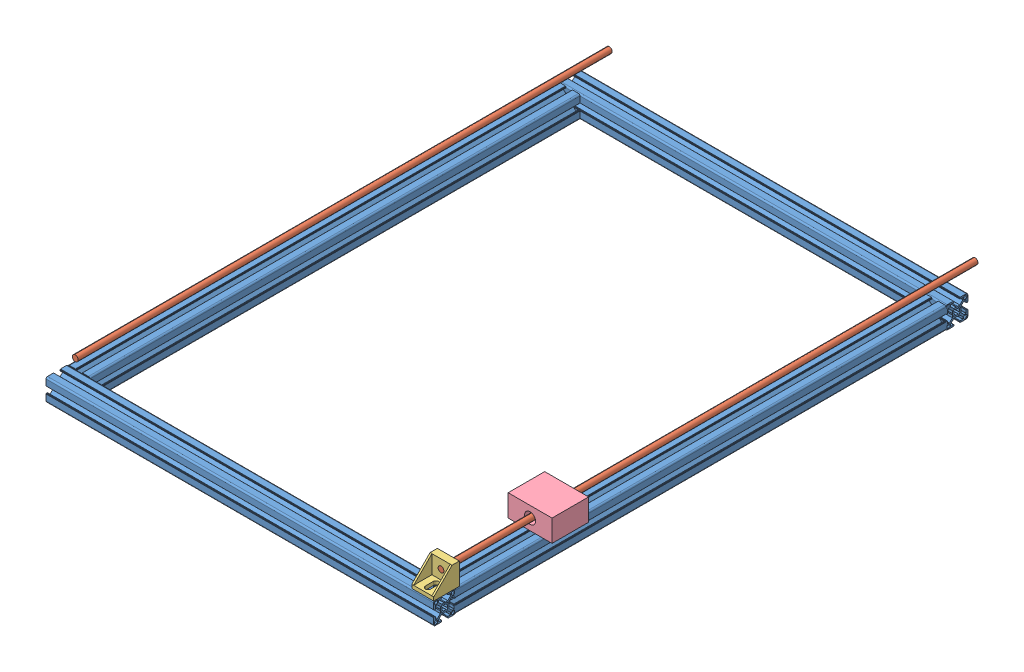
SolidWorks assembly Assem1, configuration Default. Lengths in mm.
Overall size (545 62.5 755).
4 component instances, 4 part files, 6 mates.
Components (placement in the parent):
- Alu Profil-1: Alu Profil [Default<As Machined>] at (265.2054 410.9312 543.815) x (0 0 -1) z (1 0 0) size (730 30 530)
- X Axis Rods-1: X Axis Rods [Default<As Machined>] at (265.2054 413.0471 518.815) x (0 0 -1) z (1 0 0) size (730 8 508)
- Round Profil holder-1: Round Profil holder [Default] at (515.2054 443.4312 873.815) size (30 30 35)
- X Axis Roller-1: X Axis Roller [Default] at (265.2054 443.4312 737.1166) size (60 30 50)
Mates (geometry in assembly coordinates):
- Coincident4: coincident: plane of Alu Profil-1 through (530.2054 425.9312 889.065) normal (0 1 0); plane of Round Profil holder-1 through (515.2054 425.9312 873.815) normal (0 -1 0)
- Coincident5: coincident: plane of Alu Profil-1 through (530.2054 423.9312 908.815) normal (0 0 1); plane of Round Profil holder-1 through (500.2054 425.9312 908.815) normal (0 0 1)
- Coincident6: coincident: plane of Alu Profil-1 through (530.2054 398.3312 201.865) normal (1 0 0); plane of Round Profil holder-1 through (530.2054 455.9312 883.815) normal (1 0 0)
- Concentric1: concentric: cylinder of X Axis Rods-1 through (515.2054 443.4312 166.8343) axis (0 0 1) radius 4; cylinder of Round Profil holder-1 through (515.2054 443.4312 883.815) axis (0 0 -1) radius 4
- Concentric2: concentric: cylinder of X Axis Rods-1 through (515.2054 443.4312 153.815) axis (0 0 1) radius 4; cylinder of X Axis Roller-1 through (515.2054 443.4312 762.1166) axis (0 0 -1) radius 7.5
- Coincident7: coincident: plane of X Axis Rods-1 through (515.2054 443.4312 883.815) normal (0 0 1); plane of Round Profil holder-1 through (515.2054 443.4312 883.815) normal (0 0 1)
